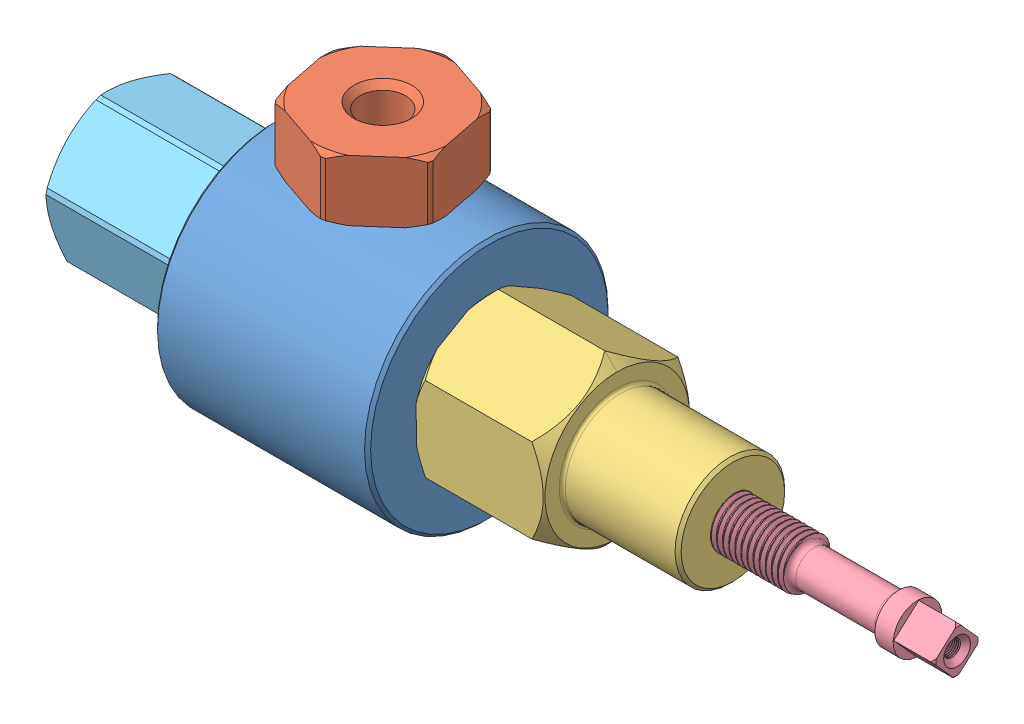
SolidWorks assembly SBORKA, configuration Default. Lengths in mm.
Overall size (138.81 51 40).
5 component instances, 5 part files, 12 mates.
Components (placement in the parent):
- baza-1: baza [По умолчанию] at (23.2114 -39.6079 106.5734) size (72.84 40 40)
- bolt-1-1: bolt-1 [По умолчанию] at (62.7114 -8.6079 106.5734) x (-0.752155 0 0.658987) z (0.658987 0 0.752155) size (25.4 25.55 22)
- detal-1-1: detal-1 [По умолчанию] at (80.2114 -39.6079 106.5734) x (1 0 0) z (0 -0.999997 -0.002325) size (40.76 24 27.71)
- detal-2-1: detal-2 [По умолчанию] at (150.5236 -39.6079 106.5734) x (-1 0 0) z (0 0.744544 0.667574) size (105.5 8.07 8.22)
- gayka-1-1: gayka-1 [По умолчанию] at (18.2114 -39.6079 106.5734) x (1 0 0) z (0 0.956436 0.291943) size (25 22 24.9)
Mates (geometry in assembly coordinates):
- Концентричный3: concentric aligned: cylinder of baza-1 through (62.7114 -33.6079 106.5734) axis (0 1 0) radius 7; cylinder of bolt-1-1 through (62.7114 -33.6079 106.5734) axis (0 1 0) radius 3.75
- Совпадение4: coincident anti-aligned: plane of baza-1 through (62.7114 -33.6079 106.5734) normal (0 1 0); plane of bolt-1-1 through (62.7114 -33.6079 106.5734) normal (0 -1 0)
- Концентричный4: concentric aligned: cylinder of baza-1 through (62.7114 -39.6079 106.5734) axis (0 1 0) radius 3; cylinder of bolt-1-1 through (62.7114 -33.6079 106.5734) axis (0 1 0) radius 7
- Концентричный5: concentric anti-aligned: cylinder of baza-1 through (23.2114 -39.6079 106.5734) axis (-1 0 0) radius 7; cylinder of gayka-1-1 through (23.2114 -39.6079 106.5734) axis (1 0 0) radius 7.5
- Совпадение5: coincident anti-aligned: plane of baza-1 through (23.2114 -34.1079 106.5734) normal (-1 0 0); plane of gayka-1-1 through (23.2114 -39.6079 106.5734) normal (1 0 0)
- Концентричный6: concentric aligned: cylinder of baza-1 through (23.2114 -39.6079 106.5734) axis (-1 0 0) radius 1.5; cylinder of gayka-1-1 through (43.2114 -39.6079 106.5734) axis (-1 0 0) radius 3.5
- Концентричный7: concentric aligned: cylinder of baza-1 through (23.2114 -39.6079 106.5734) axis (-1 0 0) radius 8; cylinder of detal-1-1 through (101.2114 -39.6079 106.5734) axis (-1 0 0) radius 8.5
- Совпадение7: coincident anti-aligned: plane of baza-1 through (80.2114 -19.6079 106.5734) normal (1 0 0); plane of detal-1-1 through (80.2114 -39.6079 106.5734) normal (-1 0 0)
- Концентричный8: concentric aligned: cylinder of baza-1 through (23.2114 -39.6079 106.5734) axis (-1 0 0) radius 8; cylinder of detal-1-1 through (101.2114 -39.6079 106.5734) axis (-1 0 0) radius 8.5
- Концентричный9: concentric anti-aligned: cylinder of detal-1-1 through (111.2114 -39.6079 106.5734) axis (-1 0 0) radius 9; cylinder of detal-2-1 through (150.5236 -39.6079 106.5734) axis (1 0 0) radius 3
- Касательность5: tangent: circle of baza-1; cone of detal-2-1 through (52.4407 -39.6079 106.5734) axis (-1 0 0)
- Концентричный11: concentric anti-aligned: cylinder of detal-1-1 through (111.2114 -39.6079 106.5734) axis (-1 0 0) radius 9; cylinder of detal-2-1 through (150.5236 -39.6079 106.5734) axis (1 0 0) radius 3
